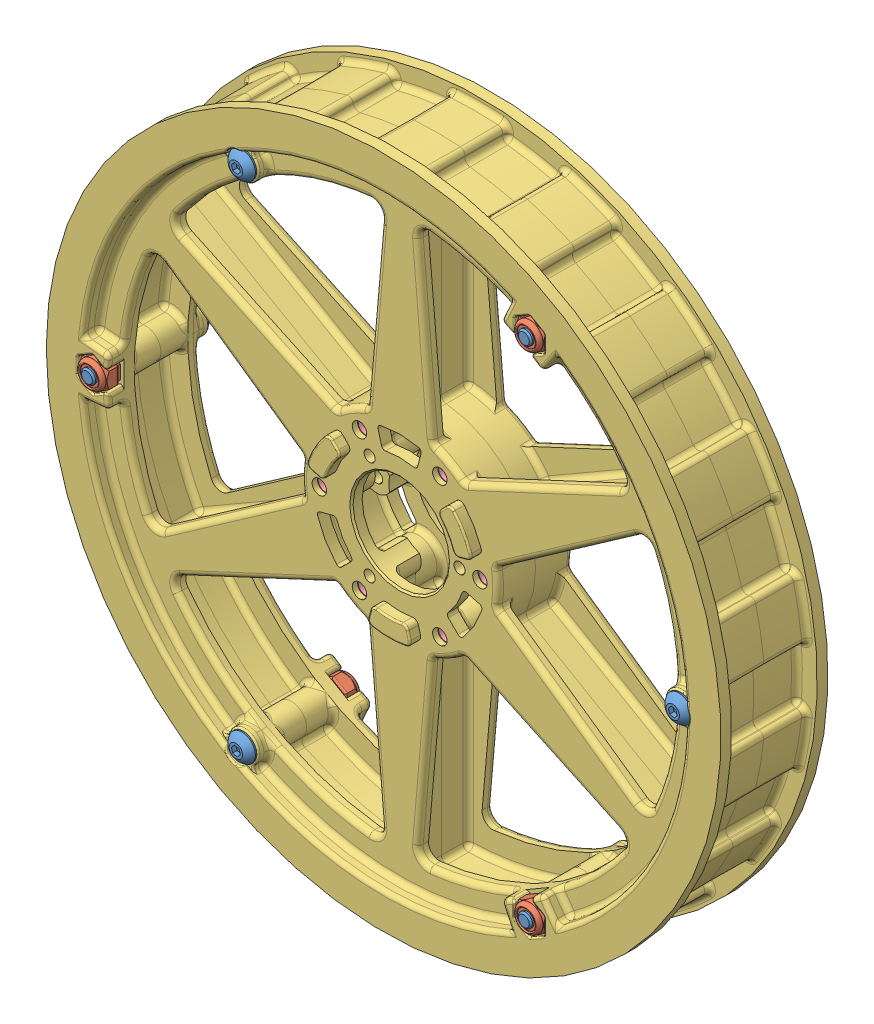
SolidWorks assembly 217-2605 1in.20121203, configuration Default. Lengths in mm.
Overall size (273.24 273.24 34.92).
20 component instances, 4 part files, 0 mates.
Components (placement in the parent):
- SBS1_SBS0832-1250SS-1: SBS1_SBS0832-1250SS [Default] at (-86.36 0 -16.4973) x (0 0 1) z (0.950435 -0.310923 0) size (34.41 8.02 7.99)
- SBS1_SBS0832-1250SS-2: SBS1_SBS0832-1250SS [Default] at (-43.18 74.79 16.4973) x (0 0 -1) z (-0.955409 -0.295284 0) size (34.41 8.02 7.99)
- NUT-832-NYLOCK-1: NUT-832-NYLOCK [Default] at (-86.36 0 12.0688) x (0.866025 0.5 0) z (0.5 -0.866025 0) size (10.2 5.86 8.12)
- NUT-832-NYLOCK-2: NUT-832-NYLOCK [Default] at (-43.18 74.79 -12.0688) x (-0.866025 -0.5 0) z (0.5 -0.866025 0) size (10.2 5.86 8.12)
- 217-2605-001 Rev1-1: 217-2605-001 Rev1 [Default] x (-0.5 0.866025 0) z (0 0 1) size (200.03 200.03 19.71)
- 217-2605-001 Rev1-2: 217-2605-001 Rev1 [Default] x (-1 0 0) z (0 0 -1) size (200.03 200.03 19.71)
- NUT-832-NYLOCK-3: NUT-832-NYLOCK [Default] at (86.36 0 -12.0688) x (0 1 0) z (-1 0 0) size (10.2 5.86 8.12)
- NUT-832-NYLOCK-4: NUT-832-NYLOCK [Default] at (-43.18 -74.79 -12.0688) x (0.866025 -0.5 0) z (0.5 0.866025 0) size (10.2 5.86 8.12)
- NUT-832-NYLOCK-5: NUT-832-NYLOCK [Default] at (43.18 74.79 12.0688) x (0 -1 0) z (-1 0 0) size (10.2 5.86 8.12)
- NUT-832-NYLOCK-6: NUT-832-NYLOCK [Default] at (43.18 -74.79 12.0688) x (-0.866025 0.5 0) z (0.5 0.866025 0) size (10.2 5.86 8.12)
- SBS1_SBS0832-1250SS-3: SBS1_SBS0832-1250SS [Default] at (43.18 74.79 -16.4973) x (0 0 1) z (-0.744485 -0.66764 0) size (34.41 8.02 7.99)
- SBS1_SBS0832-1250SS-4: SBS1_SBS0832-1250SS [Default] at (43.18 -74.79 -16.4973) x (0 0 1) z (-0.20595 0.978562 0) size (34.41 8.02 7.99)
- SBS1_SBS0832-1250SS-5: SBS1_SBS0832-1250SS [Default] at (86.36 0 16.4973) x (0 0 -1) z (0.221981 0.975051 0) size (34.41 8.02 7.99)
- SBS1_SBS0832-1250SS-6: SBS1_SBS0832-1250SS [Default] at (-43.18 -74.79 16.4973) x (0 0 -1) z (0.733429 -0.679767 0) size (34.41 8.02 7.99)
- BEAM-0750-1: BEAM-0750 [Default] at (-23.8125 0 0) x (0.866025 0.5 0) z (-0.5 0.866025 0) size (7.34 19.93 7.34)
- BEAM-0750-2: BEAM-0750 [Default] at (-11.9062 20.6222 0) x (0.866025 -0.5 0) z (0.5 0.866025 0) size (7.34 19.93 7.34)
- BEAM-0750-3: BEAM-0750 [Default] at (11.9062 20.6222 0) x (0 -1 0) z (1 0 0) size (7.34 19.93 7.34)
- BEAM-0750-4: BEAM-0750 [Default] at (23.8125 0 0) x (-0.866025 -0.5 0) z (0.5 -0.866025 0) size (7.34 19.93 7.34)
- BEAM-0750-5: BEAM-0750 [Default] at (11.9062 -20.6222 0) x (-0.866025 0.5 0) z (-0.5 -0.866025 0) size (7.34 19.93 7.34)
- BEAM-0750-6: BEAM-0750 [Default] at (-11.9062 -20.6222 0) x (0 1 0) z (-1 0 0) size (7.34 19.93 7.34)
